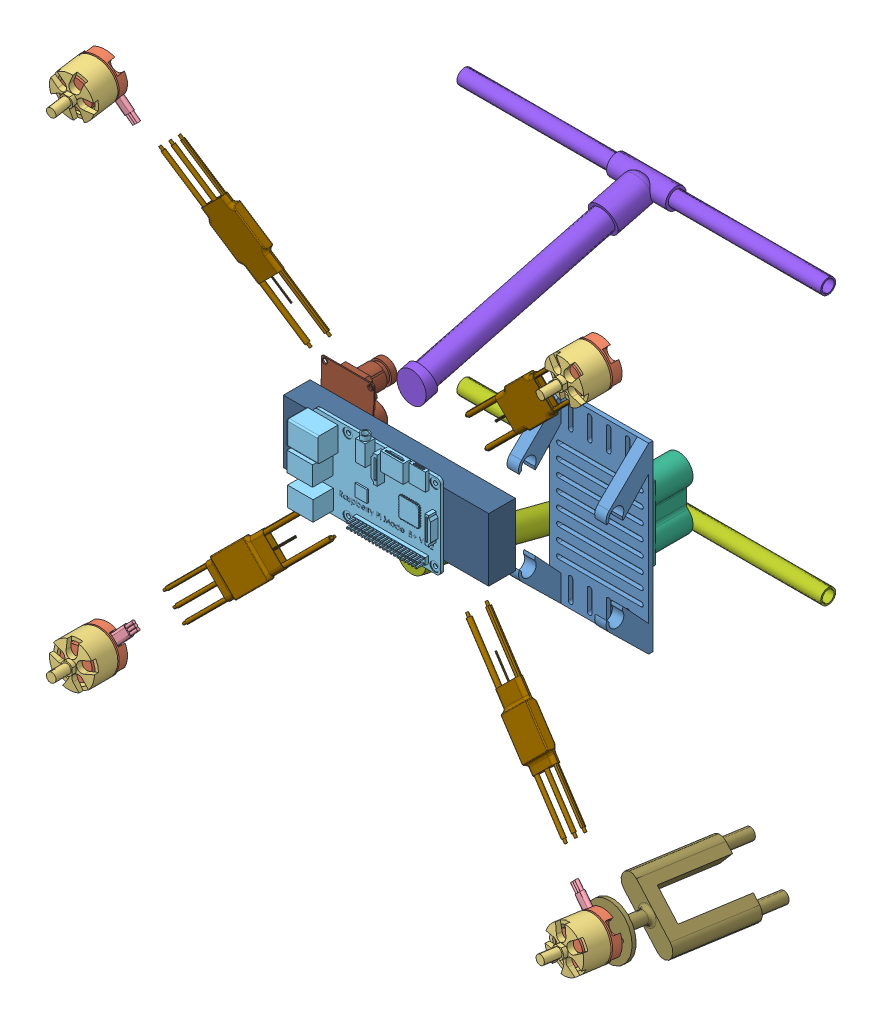
SolidWorks assembly Complete Drone, configuration Default. Lengths in mm.
Overall size (400.31 607.9 398.02).
38 component instances, 16 part files, 55 mates.
Components (placement in the parent):
- S500 Frame-1: S500 Frame [Default] at (72.5801 224.1097 294.7299) size (374.52 374.52 61.06)
- LIDAR Mount-1: LIDAR Mount [Default] at (197.5801 194.1097 281.7299) x (0 -1 0) z (-1 0 0) size (121.8 31.17 66.04)
- User Library-emaxmodel-mt2213-1: User Library-emaxmodel-mt2213 [По умолчанию] at (238.5265 390.0562 331.8046) x (0.997236 0.002051 0.074267) z (0.007529 -0.997263 -0.073557) size (36.98 47 36.98)
  - User Library-emaxmodel-mt2213_emaxmodel-mt2213-stator-1: User Library-emaxmodel-mt2213_emaxmodel-mt2213-stator [По умолчанию] at origin size (28 21 28)
  - User Library-emaxmodel-mt2213_emaxmodel-mt2213-rotor-1: User Library-emaxmodel-mt2213_emaxmodel-mt2213-rotor [По умолчанию] at (0 7 0) x (0.999557 0 0.02976) z (-0.02976 0 0.999557) size (28 32 28)
  - User Library-emaxmodel-mt2213_emaxmodel-mt2213-cone-1: User Library-emaxmodel-mt2213_emaxmodel-mt2213-cone [По умолчанию] at (0 32 0) size (12 15 13.86)
  - User Library-emaxmodel-mt2213_wires-1: User Library-emaxmodel-mt2213_wires [По умолчанию] at (-15.8508 1.5 15.8508) x (0.707107 0 0.707107) z (-0.707107 0 0.707107) size (7 3 19)
- User Library-emaxmodel-mt2213-2: User Library-emaxmodel-mt2213 [По умолчанию] at (-93.3664 58.1632 331.8046) x (-0.996096 -0.042797 0.07721) z (-0.048269 0.996346 -0.070461) size (36.98 47 36.98)
  - User Library-emaxmodel-mt2213_emaxmodel-mt2213-stator-1: User Library-emaxmodel-mt2213_emaxmodel-mt2213-stator [По умолчанию] at origin size (28 21 28)
  - User Library-emaxmodel-mt2213_emaxmodel-mt2213-rotor-1: User Library-emaxmodel-mt2213_emaxmodel-mt2213-rotor [По умолчанию] at (0 7 0) x (0.999557 0 0.02976) z (-0.02976 0 0.999557) size (28 32 28)
  - User Library-emaxmodel-mt2213_emaxmodel-mt2213-cone-1: User Library-emaxmodel-mt2213_emaxmodel-mt2213-cone [По умолчанию] at (0 32 0) size (12 15 13.86)
  - User Library-emaxmodel-mt2213_wires-1: User Library-emaxmodel-mt2213_wires [По умолчанию] at (-15.8508 1.5 15.8508) x (0.707107 0 0.707107) z (-0.707107 0 0.707107) size (7 3 19)
- User Library-emaxmodel-mt2213-3: User Library-emaxmodel-mt2213 [По умолчанию] at (-93.3664 390.0562 331.8046) x (0.025833 0.997057 0.072181) z (0.99693 -0.020357 -0.075605) size (36.98 47 36.98)
  - User Library-emaxmodel-mt2213_emaxmodel-mt2213-stator-1: User Library-emaxmodel-mt2213_emaxmodel-mt2213-stator [По умолчанию] at origin size (28 21 28)
  - User Library-emaxmodel-mt2213_emaxmodel-mt2213-rotor-1: User Library-emaxmodel-mt2213_emaxmodel-mt2213-rotor [По умолчанию] at (0 7 0) x (0.999557 0 0.02976) z (-0.02976 0 0.999557) size (28 32 28)
  - User Library-emaxmodel-mt2213_emaxmodel-mt2213-cone-1: User Library-emaxmodel-mt2213_emaxmodel-mt2213-cone [По умолчанию] at (0 32 0) size (12 15 13.86)
  - User Library-emaxmodel-mt2213_wires-1: User Library-emaxmodel-mt2213_wires [По умолчанию] at (-15.8508 1.5 15.8508) x (0.707107 0 0.707107) z (-0.707107 0 0.707107) size (7 3 19)
- User Library-emaxmodel-mt2213-4: User Library-emaxmodel-mt2213 [По умолчанию] at (238.5265 58.1632 331.8046) x (0.007659 -0.997178 0.074679) z (-0.997235 -0.013136 -0.073138) size (36.98 47 36.98)
  - User Library-emaxmodel-mt2213_emaxmodel-mt2213-stator-1: User Library-emaxmodel-mt2213_emaxmodel-mt2213-stator [По умолчанию] at origin size (28 21 28)
  - User Library-emaxmodel-mt2213_emaxmodel-mt2213-rotor-1: User Library-emaxmodel-mt2213_emaxmodel-mt2213-rotor [По умолчанию] at (0 7 0) x (0.999557 0 0.02976) z (-0.02976 0 0.999557) size (28 32 28)
  - User Library-emaxmodel-mt2213_emaxmodel-mt2213-cone-1: User Library-emaxmodel-mt2213_emaxmodel-mt2213-cone [По умолчанию] at (0 32 0) size (12 15 13.86)
  - User Library-emaxmodel-mt2213_wires-1: User Library-emaxmodel-mt2213_wires [По умолчанию] at (-15.8508 1.5 15.8508) x (0.707107 0 0.707107) z (-0.707107 0 0.707107) size (7 3 19)
- Raspberry Pi-1: Raspberry Pi [Default] at (74.4168 224.653 316.2299) x (1 0 0) z (0 -1 0) size (89.47 15.5 61.14)
- User Library-LIDAR-Lite_v3-1: User Library-LIDAR-Lite_v3 [Default] at (174.8801 224.0933 257.4202) x (0 -1 0) z (0 0 -1) size (48.5 35.6 40)
- Hélice_1045-1: Hélice_1045 [Predeterminado] at (236.2737 387.8033 362.1176) x (-0.992571 -0.091184 -0.080545) z (0.096638 -0.993087 -0.066624) size (43.07 30.39 271.54)
- Hélice_1045-2: Hélice_1045 [Predeterminado] at (236.6772 60.0125 356.6875) x (0.995422 -0.055121 0.078076) z (-0.06059 -0.99574 0.0695) size (43.07 30.39 271.54)
- Hélice_1045-3: Hélice_1045 [Predeterminado] at (-91.5171 60.0125 356.6875) x (-0.991571 0.111859 0.06538) z (0.106414 0.990971 -0.081558) size (43.07 30.39 271.54)
- Hélice_1045-4: Hélice_1045 [Predeterminado] at (-91.1136 387.8033 362.1176) x (0.99396 -0.075661 -0.079494) z (0.081122 0.99439 0.067874) size (43.07 30.39 271.54)
- Drone Legs-1: Drone Legs [Default] at (195.2301 134.5438 138.1528) x (0 -0.967884 0.251398) z (-1 0 0) size (19.56 171.15 242.57)
- Drone Legs Right-1: Drone Legs Right [Default] at (195.2301 313.6756 138.1528) x (0 -0.967884 -0.251398) z (-1 0 0) size (19.56 171.15 242.57)
- 30A ESC-1: 30A ESC [Default] at (166.8316 147.9576 305.3085) x (0.707107 0.707107 0) z (0.69963 -0.69963 0.145038) size (28.83 9.95 119.13)
- 30A ESC-2: 30A ESC [Default] at (-3.8513 129.5788 305.3664) x (0.707107 -0.707107 0) z (-0.69963 -0.69963 0.145038) size (28.83 9.95 119.13)
- 30A ESC-3: 30A ESC [Default] at (-4.7202 319.5053 311.4505) x (0.707107 0.707107 0) z (-0.69963 0.69963 0.145038) size (28.83 9.95 119.13)
- 30A ESC-4: 30A ESC [Default] at (167.8781 301.3124 311.4303) x (0.707107 -0.707107 0) z (0.69963 0.69963 0.145038) size (28.83 9.95 119.13)
- LiPO Battery-1: LiPO Battery [Default] at (76.2671 224.0547 296.2299) size (136.91 41.91 17.78)
- S500 Frame - Copy-1: S500 Frame - Copy [Default] at (-56.5902 224.1097 294.7299) size (100 71.1 41.02)
- PX4Flow-1: PX4Flow [Default] at (-15.3051 192.2912 248.205) x (-0.004384 -0.99999 0) z (0.99999 -0.004384 0) size (45.5 29.45 35)
- Float Mount-1: Float Mount [Default] at (238.8094 57.7789 328.3349) x (-0.997248 0.000375 -0.074143) z (0.073913 -0.073913 -0.994522) size (39.26 35.07 99.06) (hidden)
Mates (geometry in assembly coordinates):
- Concentric8: concentric aligned: circle of S500 Frame-1; circle of User Library-emaxmodel-mt2213-3/User Library-emaxmodel-mt2213_emaxmodel-mt2213-stator-1
- Coincident4: coincident anti-aligned: plane of S500 Frame-1 through (-121.5693 391.389 333.9997) normal (0.073913 -0.073913 0.994522); plane of User Library-emaxmodel-mt2213-3/User Library-emaxmodel-mt2213_emaxmodel-mt2213-stator-1 through (-93.3664 390.0562 331.8046) normal (-0.073913 0.073913 -0.994522)
- Concentric9: concentric aligned: circle of S500 Frame-1; circle of User Library-emaxmodel-mt2213-1/User Library-emaxmodel-mt2213_emaxmodel-mt2213-stator-1
- Coincident5: coincident anti-aligned: plane of S500 Frame-1 through (239.8594 418.2591 333.9997) normal (-0.073913 -0.073913 0.994522); plane of User Library-emaxmodel-mt2213-1/User Library-emaxmodel-mt2213_emaxmodel-mt2213-stator-1 through (238.5265 390.0562 331.8046) normal (0.073913 0.073913 -0.994522)
- Concentric10: concentric aligned: circle of S500 Frame-1; circle of User Library-emaxmodel-mt2213-4/User Library-emaxmodel-mt2213_emaxmodel-mt2213-stator-1
- Coincident7: coincident anti-aligned: plane of S500 Frame-1 through (266.7295 56.8304 333.9997) normal (-0.073913 0.073913 0.994522); plane of User Library-emaxmodel-mt2213-4/User Library-emaxmodel-mt2213_emaxmodel-mt2213-stator-1 through (238.5265 58.1632 331.8046) normal (0.073913 -0.073913 -0.994522)
- Concentric11: concentric aligned: circle of S500 Frame-1; circle of User Library-emaxmodel-mt2213-2/User Library-emaxmodel-mt2213_emaxmodel-mt2213-stator-1
- Coincident8: coincident anti-aligned: plane of S500 Frame-1 through (-94.6993 29.9603 333.9997) normal (0.073913 0.073913 0.994522); plane of User Library-emaxmodel-mt2213-2/User Library-emaxmodel-mt2213_emaxmodel-mt2213-stator-1 through (-93.3664 58.1632 331.8046) normal (-0.073913 -0.073913 -0.994522)
- Coincident9: coincident anti-aligned: plane of S500 Frame-1 through (72.5801 224.1097 316.2299) normal (0 0 1); plane of Raspberry Pi-1 through (74.4168 224.653 316.2299) normal (0 0 -1)
- Distance1: distance = 50.6633 mm aligned: plane of Raspberry Pi-1 through (116.9168 252.653 318.2299) normal (1 0 0); plane of S500 Frame-1 through (167.5801 195.6097 294.7299) normal (1 0 0)
- Distance2: distance = 31.5433 mm aligned: plane of Raspberry Pi-1 through (31.9168 196.653 318.2299) normal (0 -1 0); plane of S500 Frame-1 through (34.7064 165.1097 294.7299) normal (0 -1 0)
- Concentric12: concentric anti-aligned: circle of S500 Frame-1; circle of LIDAR Mount-1
- Coincident12: coincident aligned: plane of S500 Frame-1 through (197.5801 194.1097 281.7299) normal (1 0 0); plane of LIDAR Mount-1 through (197.5801 194.1097 281.7299) normal (1 0 0)
- Parallel4: parallel aligned: plane of S500 Frame-1 through (70.0801 224.1097 296.2299) normal (0 0 1); plane of LIDAR Mount-1 through (189.9601 194.1097 260.2208) normal (0 0 1)
- Coincident16: coincident anti-aligned: plane of LIDAR Mount-1 through (197.5801 194.1097 257.4202) normal (0 0 -1); plane of User Library-LIDAR-Lite_v3-1 through (174.8801 224.0933 257.4202) normal (0 0 1)
- Distance3: distance = 12.7 mm aligned: plane of User Library-LIDAR-Lite_v3-1 through (184.8801 231.5933 257.4202) normal (1 0 0); plane of LIDAR Mount-1 through (197.5801 194.1097 281.7299) normal (1 0 0)
- Distance4: distance = 36.83 mm aligned: plane of User Library-LIDAR-Lite_v3-1 through (164.8801 248.3433 254.8002) normal (0 1 0); plane of LIDAR Mount-1 through (189.9601 285.1733 281.7299) normal (0 1 0)
- Concentric15: concentric anti-aligned: cylinder of User Library-emaxmodel-mt2213-4/User Library-emaxmodel-mt2213_emaxmodel-mt2213-rotor-1 through (235.6439 61.0458 370.5909) axis (0.073913 -0.073913 -0.994522) radius 3; circle of Hélice_1045-2
- Distance6: distance = 30.48 mm aligned: plane of Hélice_1045-2 through (236.2737 60.4161 362.1176) normal (-0.073913 0.073913 0.994522); plane of S500 Frame-1 through (266.7295 56.8304 333.9997) normal (-0.073913 0.073913 0.994522)
- Concentric16: concentric anti-aligned: cylinder of User Library-emaxmodel-mt2213-1/User Library-emaxmodel-mt2213_emaxmodel-mt2213-rotor-1 through (235.6439 387.1736 370.5909) axis (0.073913 0.073913 -0.994522) radius 3; circle of Hélice_1045-1
- Distance7: distance = 30.48 mm aligned: plane of Hélice_1045-1 through (229.654 455.8298 366.6814) normal (-0.073913 -0.073913 0.994522); plane of S500 Frame-1 through (239.8594 418.2591 333.9997) normal (-0.073913 -0.073913 0.994522)
- Concentric17: concentric aligned: cylinder of User Library-emaxmodel-mt2213-3/User Library-emaxmodel-mt2213_emaxmodel-mt2213-rotor-1 through (-90.4838 387.1736 370.5909) axis (-0.073913 0.073913 -0.994522) radius 3; circle of Hélice_1045-4
- Distance8: distance = 30.48 mm aligned: plane of Hélice_1045-4 through (-96.6704 319.6876 357.4682) normal (0.073913 -0.073913 0.994522); plane of S500 Frame-1 through (-121.5693 391.389 333.9997) normal (0.073913 -0.073913 0.994522)
- Concentric18: concentric anti-aligned: cylinder of User Library-emaxmodel-mt2213-2/User Library-emaxmodel-mt2213_emaxmodel-mt2213-rotor-1 through (-90.4838 61.0458 370.5909) axis (-0.073913 -0.073913 -0.994522) radius 3; circle of Hélice_1045-3
- Distance9: distance = 30.48 mm aligned: plane of Hélice_1045-3 through (-91.1136 60.4161 362.1176) normal (0.073913 0.073913 0.994522); plane of S500 Frame-1 through (-94.6993 29.9603 333.9997) normal (0.073913 0.073913 0.994522)
- Coincident17: coincident anti-aligned: plane of S500 Frame-1 through (70.0801 224.1097 294.7299) normal (0 0 -1); plane of Drone Legs-1 through (-47.3399 185.3167 294.7299) normal (0 0 1)
- Parallel6: parallel aligned: plane of S500 Frame-1 through (-52.4199 254.1097 281.7299) normal (-1 0 0); plane of Drone Legs-1 through (-47.3399 134.5438 138.1528) normal (-1 0 0)
- Tangent5: tangent: line of S500 Frame-1 through (35.9491 165.1097 294.7299) axis (1 0 0); curve of Drone Legs-1
- Distance11: distance = 5.08 mm aligned: plane of S500 Frame-1 through (-52.4199 194.1097 281.7299) normal (-1 0 0); plane of Drone Legs-1 through (-47.3399 134.5438 138.1528) normal (-1 0 0)
- Coincident20: coincident anti-aligned: plane of S500 Frame-1 through (70.0801 224.1097 294.7299) normal (0 0 -1); plane of Drone Legs Right-1 through (-47.3399 283.1097 294.7299) normal (0 0 1)
- Distance12: distance = 5.08 mm aligned: plane of Drone Legs Right-1 through (-47.3399 313.6756 138.1528) normal (-1 0 0); plane of S500 Frame-1 through (-52.4199 254.1097 281.7299) normal (-1 0 0)
- Tangent6: tangent: line of S500 Frame-1 through (109.211 283.1097 294.7299) axis (-1 0 0); curve of Drone Legs Right-1
- Coincident21: coincident anti-aligned: plane of 30A ESC-4 through (167.8781 301.3124 311.4303) normal (-0.102557 -0.102557 0.989426); plane of S500 Frame-1 through (120.3098 298.7095 306.2299) normal (0.102557 0.102557 -0.989426)
- Tangent7: tangent anti-aligned: cylinder of S500 Frame-1 through (430.5016 85.5638 323.4423) axis (-0.073913 -0.073913 0.994522) radius 339.0556; plane of 30A ESC-4 through (160.5898 295.1489 304.1315) normal (0.707107 -0.707107 0)
- Lock1: lock: unknown of S500 Frame-1; unknown of 30A ESC-4
- Coincident26: coincident anti-aligned: plane of S500 Frame-1 through (-2.0197 271.8394 306.2299) normal (-0.102557 0.102557 -0.989426); plane of 30A ESC-3 through (-4.7202 319.5053 311.4505) normal (0.102557 -0.102557 0.989426)
- Tangent8: tangent anti-aligned: cylinder of S500 Frame-1 through (211.126 582.0313 323.4423) axis (0.073913 -0.073913 0.994522) radius 339.0556; plane of 30A ESC-3 through (1.4433 312.217 304.1517) normal (0.707107 0.707107 0)
- Lock2: lock: unknown of S500 Frame-1; unknown of 30A ESC-3
- Coincident27: coincident anti-aligned: plane of 30A ESC-1 through (166.2325 148.5568 311.0887) normal (-0.102557 0.102557 0.989426); plane of S500 Frame-1 through (147.1798 176.38 306.2299) normal (0.102557 -0.102557 -0.989426)
- Tangent10: tangent anti-aligned: cylinder of S500 Frame-1 through (-65.9659 -133.8119 323.4423) axis (-0.073913 0.073913 0.994522) radius 339.0556; plane of 30A ESC-1 through (141.3724 138.3468 309.5702) normal (-0.707107 -0.707107 0)
- Lock3: lock: unknown of S500 Frame-1; unknown of 30A ESC-1
- Coincident29: coincident anti-aligned: plane of S500 Frame-1 through (24.8503 149.5099 306.2299) normal (-0.102557 -0.102557 -0.989426); plane of 30A ESC-2 through (-3.2522 130.1779 311.1466) normal (0.102557 0.102557 0.989426)
- Tangent13: tangent anti-aligned: cylinder of S500 Frame-1 through (-285.3415 362.6556 323.4423) axis (0.073913 0.073913 0.994522) radius 339.0556; plane of 30A ESC-2 through (-13.4622 155.038 309.6281) normal (-0.707107 0.707107 0)
- Lock4: lock: unknown of S500 Frame-1; unknown of 30A ESC-2
- Coincident30: coincident anti-aligned: plane of S500 Frame-1 through (70.0801 224.1097 296.2299) normal (0 0 1); plane of LiPO Battery-1 through (76.2671 224.0547 296.2299) normal (0 0 -1)
- Distance15: distance = 22.86 mm aligned: plane of LiPO Battery-1 through (144.7201 203.0997 314.0099) normal (1 0 0); plane of S500 Frame-1 through (167.5801 195.6097 294.7299) normal (1 0 0)
- Distance16: distance = 38.1 mm aligned: plane of LiPO Battery-1 through (144.7201 245.0097 314.0099) normal (0 1 0); plane of S500 Frame-1 through (110.4537 283.1097 294.7299) normal (0 1 0)
- Concentric19: concentric anti-aligned: circle of S500 Frame-1; circle of S500 Frame - Copy-1
- Concentric20: concentric anti-aligned: circle of S500 Frame-1; circle of S500 Frame - Copy-1
- Coincident36: coincident aligned: plane of S500 Frame-1 through (-52.4199 254.1097 281.7299) normal (-1 0 0); plane of S500 Frame - Copy-1 through (-52.4199 224.1097 269.7174) normal (-1 0 0)
- Coincident37: coincident anti-aligned: plane of S500 Frame - Copy-1 through (-12.4199 224.1097 248.205) normal (0 0 -1); plane of PX4Flow-1 through (1.0956 170.4711 248.205) normal (0 0 1)
- Concentric25: concentric aligned: circle of S500 Frame - Copy-1; circle of PX4Flow-1
- Lock5: lock: unknown of S500 Frame - Copy-1; unknown of PX4Flow-1
- Coincident38: coincident anti-aligned: plane of S500 Frame-1 through (238.7852 57.9045 328.3238) normal (0.073913 -0.073913 -0.994522); plane of Float Mount-1 through (238.8094 57.7789 328.3349) normal (-0.073913 0.073913 0.994522)
- Concentric26: concentric anti-aligned: circle of S500 Frame-1; circle of Float Mount-1
